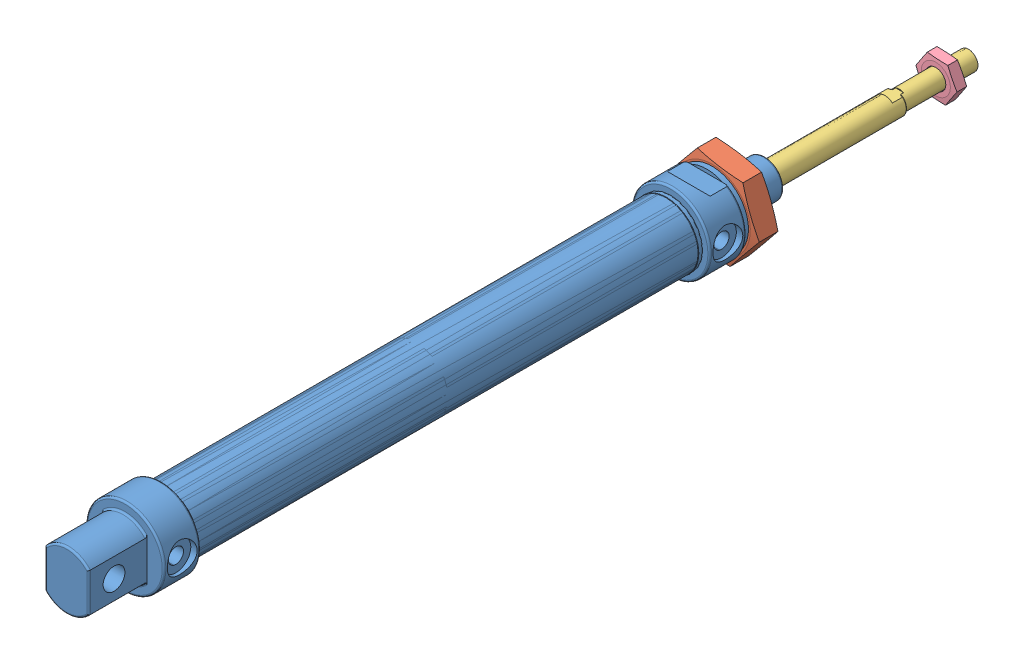
SolidWorks assembly 16 X 100 Cylinder, configuration Default. Lengths in mm.
Overall size (28.61 25.8 247.92).
4 component instances, 4 part files, 0 mates.
Components (placement in the parent):
- 16 X 100 Cylinder bore-1: 16 X 100 Cylinder bore [Default] at origin size (21.5 21.5 192)
- Nut 16-1: Nut 16 [Default] at (0 0 -84.4173) x (0.986962 -0.160953 0) z (-0.160953 -0.986962 0) size (25.4 6 22)
- Rod-1: Rod [Default] at (0 0 13.0842) x (0.024302 0.999705 0) z (-0.999705 0.024302 0) size (6.2 165 6.2)
- Nut 5-1: Nut 5 [Default] at (0 0 -144.4158) x (0.997949 -0.06401 0) z (0.06401 0.997949 0) size (11.32 3 9.8)
